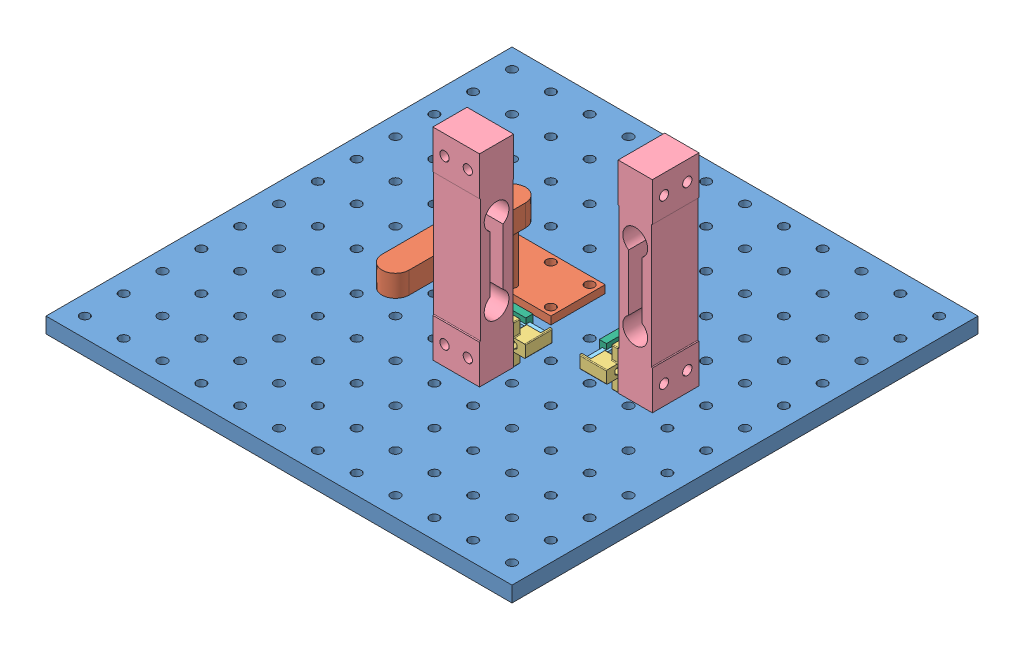
SolidWorks assembly 어셈블리1, configuration 기본. Lengths in mm.
Overall size (300 166.85 300).
10 component instances, 6 part files, 27 mates.
Components (placement in the parent):
- platform-1: platform [기본] at (-708.9249 -138.0932 300) size (300 10 300)
- finger_model-1: finger_model [기본] at (-721.4249 -128.0932 287.5) size (60 55 113.75)
- linear_guide_holder_vertical_axis-1: linear_guide_holder_vertical_axis [기본] at (-608.47 -92.3006 317.1112) x (0 1 0) z (-1 0 0) size (25 45 17.5)
- Loadcell-1: Loadcell [기본] at (-597.47 -39.8006 302.1112) x (0 1 0) z (0 0 1) size (130 22 30)
- linear_guide_holder_vertical_axis-2: linear_guide_holder_vertical_axis [기본] at (-667.9531 -88.7391 354.9094) x (0 -1 0) z (0 0 -1) size (25 45 17.5)
- Loadcell-2: Loadcell [기본] at (-652.9531 -36.2391 365.9094) x (0 1 0) z (-1 0 0) size (130 22 30)
- linear_guide_part1-1: linear_guide_part1 [기본] at (-667.9531 -88.7391 339.4094) x (1 0 0) z (0 -1 0) size (40 4 5)
- linear_guide_part2-1: linear_guide_part2 [기본] at (-666.5401 -88.7391 342.0094) x (-1 0 0) z (0 -1 0) size (17 4.6 12)
- linear_guide_part1-2: linear_guide_part1 [기본] at (-619.97 -92.3006 317.1112) x (0 0 -1) z (0 1 0) size (40 4 5)
- linear_guide_part2-2: linear_guide_part2 [기본] at (-621.37 -92.3006 318.2602) x (0 0 1) z (0 -1 0) size (17 4.6 12)
Mates (geometry in assembly coordinates):
- 동심1: concentric aligned: cylinder of platform-1 through (-696.4249 -128.0932 287.5) axis (0 -1 0) radius 3; cylinder of finger_model-1 through (-696.4249 -123.0932 287.5) axis (0 -1 0) radius 3
- 동심2: concentric aligned: cylinder of platform-1 through (-746.4249 -128.0932 287.5) axis (0 -1 0) radius 3; cylinder of finger_model-1 through (-746.4249 -123.0932 287.5) axis (0 -1 0) radius 3
- 일치1: coincident anti-aligned: plane of platform-1 through (-708.9249 -128.0932 300) normal (0 1 0); plane of finger_model-1 through (-721.4249 -128.0932 287.5) normal (0 -1 0)
- 일치2: coincident anti-aligned: plane of linear_guide_holder_vertical_axis-1 through (-608.47 -92.3006 317.1112) normal (1 0 0); plane of Loadcell-1 through (-608.47 -104.8006 332.1112) normal (-1 0 0)
- 동심3: concentric anti-aligned: cylinder of linear_guide_holder_vertical_axis-1 through (-612.47 -92.3006 309.6112) axis (1 0 0) radius 3.2; cylinder of Loadcell-1 through (-577.9848 -92.3006 309.6112) axis (-1 0 0) radius 3
- 동심4: concentric anti-aligned: cylinder of linear_guide_holder_vertical_axis-1 through (-612.47 -92.3006 324.6112) axis (1 0 0) radius 3.2; cylinder of Loadcell-1 through (-577.9848 -92.3006 324.6112) axis (-1 0 0) radius 3
- 평행1: parallel aligned: plane of platform-1 through (-558.9249 -128.0932 150) normal (1 0 0); plane of Loadcell-1 through (-586.47 -104.8006 332.1112) normal (1 0 0)
- 평행2: parallel anti-aligned: plane of platform-1 through (-708.9249 -128.0932 300) normal (0 1 0); plane of Loadcell-1 through (-608.47 -104.8006 332.1112) normal (0 -1 0)
- 평행3: parallel anti-aligned: plane of platform-1 through (-708.9249 -128.0932 300) normal (0 1 0); plane of Loadcell-2 through (-682.9531 -101.2391 354.9094) normal (0 -1 0)
- 평행4: parallel aligned: plane of platform-1 through (-858.9249 -128.0932 450) normal (0 0 1); plane of Loadcell-2 through (-682.9531 -101.2391 376.9094) normal (0 0 1)
- 동심5: concentric anti-aligned: cylinder of linear_guide_holder_vertical_axis-2 through (-675.4531 -88.7391 350.9094) axis (0 0 1) radius 3.2; cylinder of Loadcell-2 through (-675.4531 -88.7391 385.3947) axis (0 0 -1) radius 3
- 동심6: concentric anti-aligned: cylinder of linear_guide_holder_vertical_axis-2 through (-660.4531 -88.7391 350.9094) axis (0 0 1) radius 3.2; cylinder of Loadcell-2 through (-660.4531 -88.7391 385.3947) axis (0 0 -1) radius 3
- 일치7: coincident anti-aligned: plane of linear_guide_holder_vertical_axis-2 through (-667.9531 -88.7391 354.9094) normal (0 0 1); plane of Loadcell-2 through (-682.9531 -101.2391 354.9094) normal (0 0 -1)
- 동심7: concentric anti-aligned: cylinder of linear_guide_holder_vertical_axis-2 through (-652.9531 -88.7391 343.4094) axis (0 0 1) radius 1.15; cylinder of linear_guide_part1-1 through (-652.9531 -88.7391 343.4094) axis (0 0 -1) radius 1.25
- 동심8: concentric anti-aligned: cylinder of linear_guide_holder_vertical_axis-2 through (-682.9531 -88.7391 343.4094) axis (0 0 1) radius 1.15; cylinder of linear_guide_part1-1 through (-682.9531 -88.7391 343.4094) axis (0 0 -1) radius 1.25
- 일치8: coincident anti-aligned: plane of linear_guide_holder_vertical_axis-2 through (-667.9531 -88.7391 343.4094) normal (0 0 -1); plane of linear_guide_part1-1 through (-667.9531 -88.7391 343.4094) normal (0 0 1)
- 너비1: width anti-aligned: plane of linear_guide_part2-1 through (-675.0401 -86.2391 359.7294) normal (0 -1 0); plane of linear_guide_part2-1 through (-675.0401 -91.2391 359.7294) normal (0 1 0); plane of linear_guide_part1-1 through (-647.9531 -86.2391 343.4094) normal (0 1 0); plane of linear_guide_part1-1 through (-647.9531 -91.2391 343.4094) normal (0 -1 0)
- 일치9: coincident anti-aligned: plane of linear_guide_part1-1 through (-667.9531 -88.7391 339.4094) normal (0 0 -1); plane of linear_guide_part2-1 through (-666.5401 -88.7391 339.4094) normal (0 0 1)
- 거리 한도1: limit distance = 13.913 mm anti-aligned: plane of linear_guide_part2-1 through (-675.0401 -82.7391 337.4094) normal (-1 0 0); plane of linear_guide_holder_vertical_axis-2 through (-688.9531 -84.7391 337.4094) normal (1 0 0)
- 거리 한도2: limit distance = 11.087 mm anti-aligned: plane of linear_guide_holder_vertical_axis-2 through (-646.9531 -84.7391 337.4094) normal (-1 0 0); plane of linear_guide_part2-1 through (-658.0401 -82.7391 337.4094) normal (1 0 0)
- 일치11: coincident anti-aligned: plane of linear_guide_holder_vertical_axis-1 through (-619.97 -92.3006 317.1112) normal (-1 0 0); plane of linear_guide_part1-2 through (-619.97 -92.3006 317.1112) normal (1 0 0)
- 동심9: concentric aligned: cylinder of linear_guide_holder_vertical_axis-1 through (-619.97 -92.3006 332.1112) axis (1 0 0) radius 1.15; cylinder of linear_guide_part1-2 through (-623.97 -92.3006 332.1112) axis (1 0 0) radius 1.25
- 동심10: concentric aligned: cylinder of linear_guide_holder_vertical_axis-1 through (-619.97 -92.3006 302.1112) axis (1 0 0) radius 1.15; cylinder of linear_guide_part1-2 through (-623.97 -92.3006 302.1112) axis (1 0 0) radius 1.25
- 너비2: width anti-aligned: plane of linear_guide_part2-2 through (-603.65 -89.8006 326.7602) normal (0 -1 0); plane of linear_guide_part2-2 through (-603.65 -94.8006 326.7602) normal (0 1 0); plane of linear_guide_part1-2 through (-623.97 -89.8006 297.1112) normal (0 1 0); plane of linear_guide_part1-2 through (-623.97 -94.8006 297.1112) normal (0 -1 0)
- 일치12: coincident anti-aligned: plane of linear_guide_part1-2 through (-623.97 -92.3006 317.1112) normal (-1 0 0); plane of linear_guide_part2-2 through (-623.97 -92.3006 318.2602) normal (1 0 0)
- 거리 한도3: limit distance = 11.351 mm anti-aligned: plane of linear_guide_holder_vertical_axis-1 through (-625.97 -96.3006 338.1112) normal (0 0 -1); plane of linear_guide_part2-2 through (-625.97 -86.3006 326.7602) normal (0 0 1)
- 거리 한도4: limit distance = 13.649 mm anti-aligned: plane of linear_guide_holder_vertical_axis-1 through (-625.97 -96.3006 296.1112) normal (0 0 1); plane of linear_guide_part2-2 through (-625.97 -86.3006 309.7602) normal (0 0 -1)
